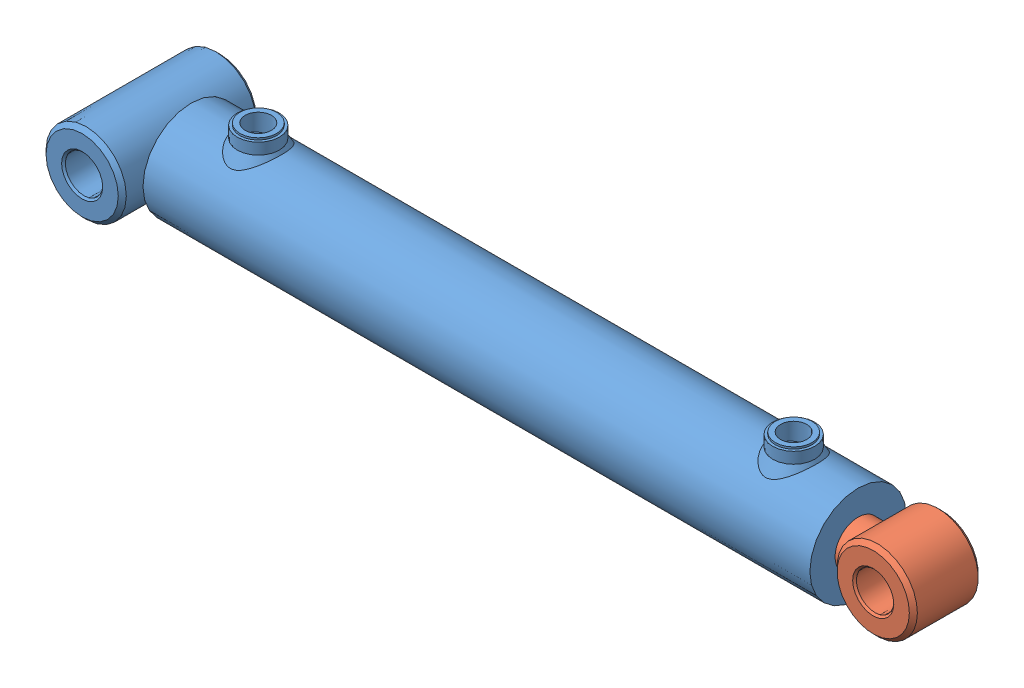
SolidWorks assembly silownik_ass, configuration Domyślna. Lengths in mm.
Overall size (364.65 49.14 60).
2 component instances, 2 part files, 4 mates.
Components (placement in the parent):
- c043220200_0_01-1: c043220200_0_01 [Default] at (-545.8618 -127.8802 0) size (325.55 49.14 60)
- c043220200_0_02-1: c043220200_0_02 [Default] at (-556.2118 -127.8802 0) size (269.45 35 30)
Mates (geometry in assembly coordinates):
- Coincident3: coincident aligned: plane of c043220200_0_01-1 through (-545.8618 -127.8802 0) normal (0 0 1)
- Coincident4: coincident aligned: plane of c043220200_0_02-1 through (-502.0445 -133.0451 0) normal (0 0 1)
- Concentric1: concentric aligned: cylinder of c043220200_0_01-1 through (-363.2759 -149.4023 0) axis (-0.993124 0.117064 0) radius 10; cylinder of c043220200_0_02-1 through (-289.4911 -158.0997 0) axis (-0.993124 0.117064 0) radius 10
- LimitDistance2: limit distance = 104.4707 mm anti-aligned: plane of c043220200_0_01-1 through (-518.3523 -131.1229 0) normal (0.993124 -0.117064 0); plane of c043220200_0_02-1 through (-414.5999 -143.3526 0) normal (-0.993124 0.117064 0)
